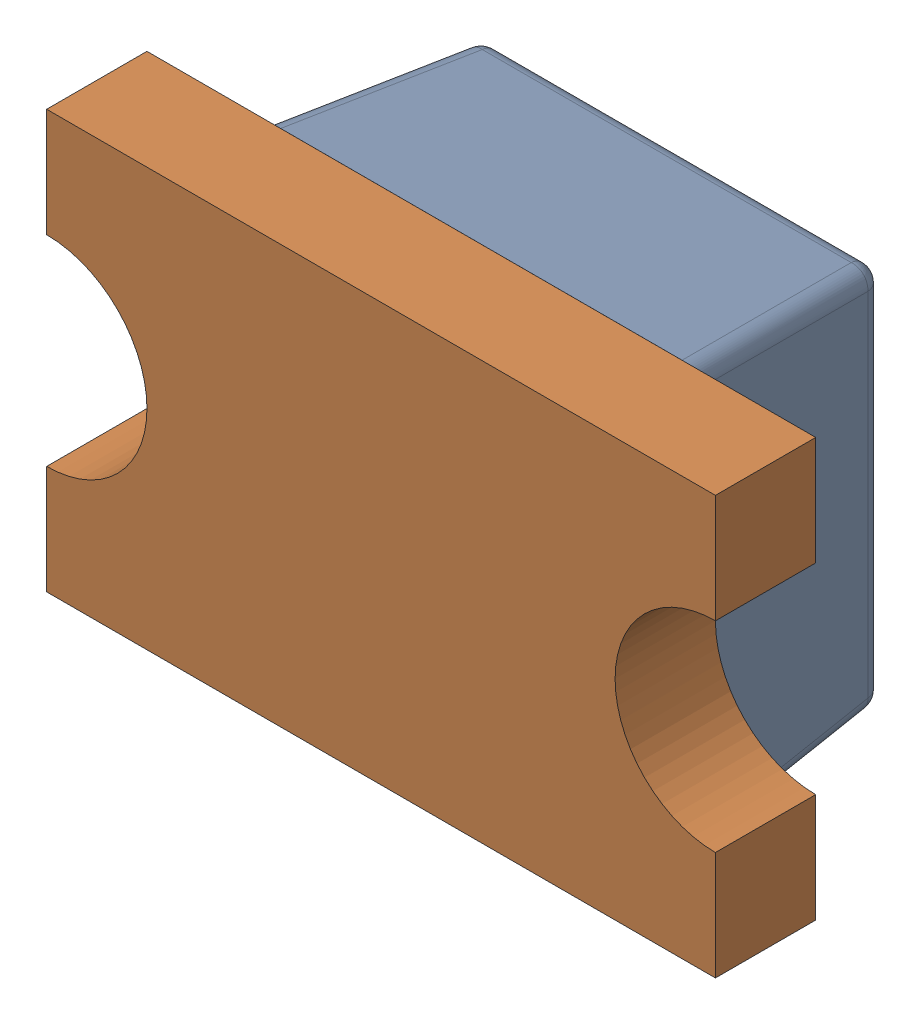
SolidWorks assembly D8_1, configuration Default. Lengths in mm.
Overall size (2 1.25 0.9).
2 component instances, 2 part files, 0 mates.
Components (placement in the parent):
- LED 0805 Lens RED-1: LED 0805 Lens RED [Default] at (76.7079 95.758 -1.2114) x (-1 0 0) z (0 -1 0) size (1.3 0.6 1.25)
- LED 0805 Base RED-1: LED 0805 Base RED [Default] at (76.7079 95.758 -1.2114) x (-1 0 0) z (0 -1 0) size (2 0.4 1.25)
